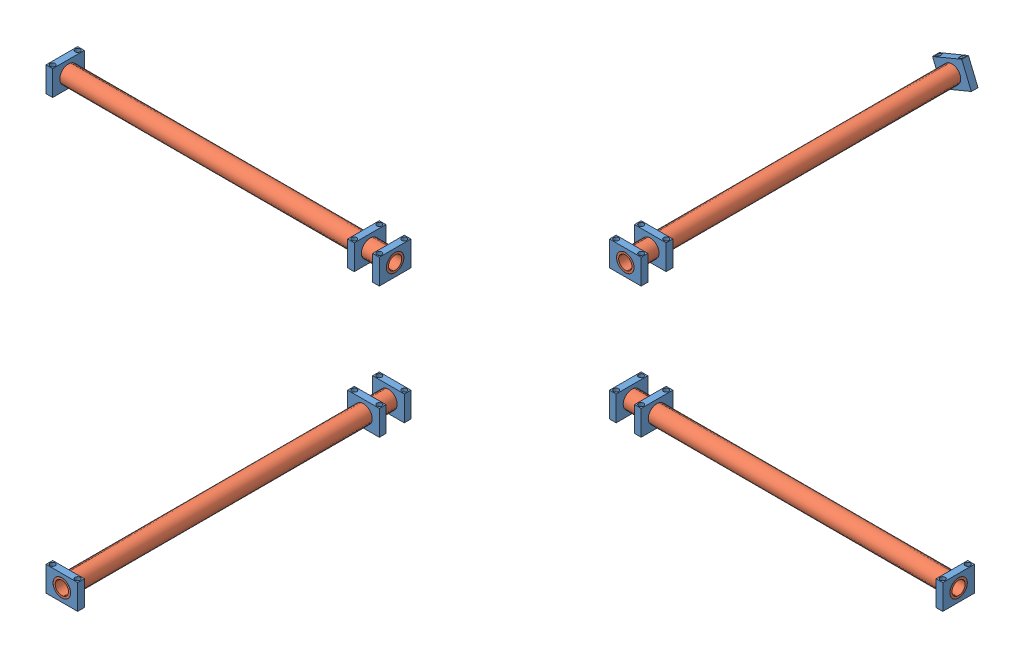
SolidWorks assembly new_drone_full_body, configuration Default. Lengths in mm.
Overall size (538.13 21.13 538.13).
18 component instances, 3 part files, 80 mates.
Components (placement in the parent):
- base-plate_drone_new-1: base-plate_drone_new [Default] at (-94378.7064 -1163.9739 82221.6136) (suppressed, hidden)
- holder-1: holder [Default] at (71.6083 102.2761 266.6718) x (1 0 0) z (0 1 0) size (19 4 15)
- holder-2: holder [Default] at (71.5935 87.2761 247.6718) x (1 0 0) z (0 -1 0) size (19 4 15)
- holder-4: holder [Default] at (12.0275 87.2761 169.1058) x (0 0 1) z (0 -1 0) size (19 4 15)
- holder-6: holder [Default] at (-6.9728 87.2761 188.1203) x (0.00014 0 -1) z (0 -1 0) size (19 4 15)
- holder-7: holder [Default] at (90.5787 102.2761 90.5398) x (-1 0 0) z (0 1 0) size (19 4 15)
- holder-8: holder [Default] at (71.5935 87.2761 105.5398) x (1 0 0) z (0 -1 0) size (19 4 15)
- holder-9: holder [Default] at (165.1595 102.2761 169.091) x (0 0 1) z (0 1 0) size (19 4 15)
- holder-10: holder [Default] at (150.1595 87.2761 188.1058) x (0 0 -1) z (0 -1 0) size (19 4 15)
- New_arm-1: New_arm [Default] at (350.1595 94.7761 178.6058) x (0 0 1) z (1 0 0) size (10.5 10.5 200)
- New_arm-2: New_arm [Default] at (81.0935 94.7761 109.5398) size (10.5 10.5 200)
- New_arm-3: New_arm [Default] at (12.0275 94.7761 178.6058) x (0 0.007654 -0.999971) z (1 0 0) size (10.5 10.5 200)
- New_arm-4: New_arm [Default] at (81.0935 94.7761 447.6718) size (10.5 10.5 200)
- base-plate_drone_new-2: base-plate_drone_new [Default] at (-94378.7064 -1146.4739 82221.6136) (suppressed, hidden)
- holder-11: holder [Default] at (69.4452 98.0651 -86.4602) x (0.923728 0.383049 0) z (-0.383049 0.923728 0) size (19 4 15)
- holder-12: holder [Default] at (-187.9725 102.2761 169.1058) x (0 0 1) z (0 1 0) size (19 4 15)
- holder-13: holder [Default] at (90.5935 102.2761 443.6718) x (-1 0 0) z (0 1 0) size (19 4 15)
- holder-14: holder [Default] at (346.1595 102.2761 169.1058) x (0 0 1) z (0 1 0) size (19 4 15)
Mates (geometry in assembly coordinates):
- Coincident6: coincident: circle of base-plate_drone_new-1; circle of holder-1
- Concentric1: concentric: circle of base-plate_drone_new-1; circle of holder-1
- Coincident8: coincident: circle of base-plate_drone_new-1; circle of holder-2
- Coincident9: coincident: circle of base-plate_drone_new-1; circle of holder-2
- Coincident16: coincident: circle of base-plate_drone_new-1; circle of holder-4
- Coincident17: coincident: circle of base-plate_drone_new-1; circle of holder-4
- Coincident20: coincident: circle of base-plate_drone_new-1; circle of holder-6
- Parallel2: parallel: cylinder of base-plate_drone_new-1 through (-4.9725 87.2761 171.1058) axis (0 -1 0) radius 1.5; cylinder of holder-6 through (-4.9704 102.2761 171.1206) axis (0 -1 0) radius 1.5
- Coincident22: coincident: circle of base-plate_drone_new-1; circle of holder-7
- Parallel3: parallel: cylinder of base-plate_drone_new-1 through (88.5935 87.2761 92.5398) axis (0 -1 0) radius 1.5; cylinder of holder-7 through (88.5787 87.2761 92.5398) axis (0 1 0) radius 1.5
- Coincident24: coincident: circle of base-plate_drone_new-1; circle of holder-8
- Coincident25: coincident: circle of base-plate_drone_new-1; circle of holder-8
- Coincident27: coincident: circle of base-plate_drone_new-1; circle of holder-9
- Parallel5: parallel: cylinder of base-plate_drone_new-1 through (167.1595 87.2761 186.1058) axis (0 -1 0) radius 1.5; cylinder of holder-9 through (167.1595 87.2761 186.091) axis (0 1 0) radius 1.5
- Coincident28: coincident: circle of base-plate_drone_new-1; circle of holder-10
- Coincident29: coincident: circle of base-plate_drone_new-1; circle of holder-10
- Concentric11: concentric: cylinder of holder-4 through (8.0275 94.7761 178.6058) axis (1 0 0) radius 5.25; cylinder of New_arm-3 through (-187.9725 94.7761 178.6058) axis (1 0 0) radius 5.25
- Coincident30: coincident: plane of holder-4 through (12.0275 87.2761 169.1058) normal (1 0 0); plane of New_arm-3 through (12.0275 94.7761 178.6058) normal (1 0 0)
- Concentric12: concentric: cylinder of holder-8 through (81.0935 94.7761 109.5398) axis (0 0 -1) radius 5.25; cylinder of New_arm-2 through (81.0935 94.7761 -90.4602) axis (0 0 1) radius 5.25
- Coincident31: coincident: plane of holder-8 through (71.5935 87.2761 109.5398) normal (0 0 1); plane of New_arm-2 through (81.0935 94.7761 109.5398) normal (0 0 1)
- Concentric13: concentric: cylinder of holder-2 through (81.0935 94.7761 251.6718) axis (0 0 -1) radius 5.25; cylinder of New_arm-4 through (81.0935 94.7761 247.6718) axis (0 0 1) radius 5.25
- Coincident32: coincident: plane of holder-2 through (71.5935 87.2761 247.6718) normal (0 0 -1); plane of New_arm-4 through (81.0935 94.7761 247.6718) normal (0 0 -1)
- Concentric14: concentric: cylinder of holder-10 through (154.1595 94.7761 178.6058) axis (-1 0 0) radius 5.25; cylinder of New_arm-1 through (150.1595 94.7761 178.6058) axis (1 0 0) radius 5.25
- Coincident33: coincident: plane of holder-10 through (150.1595 87.2761 188.1058) normal (-1 0 0); plane of New_arm-1 through (150.1595 94.7761 178.6058) normal (-1 0 0)
- Coincident34: coincident: circle of holder-7; circle of base-plate_drone_new-2
- Parallel6: parallel: cylinder of holder-7 through (88.5787 87.2761 92.5398) axis (0 1 0) radius 1.5; cylinder of base-plate_drone_new-2 through (88.5935 104.7761 92.5398) axis (0 -1 0) radius 1.5
- Coincident36: coincident: circle of holder-8; circle of base-plate_drone_new-2
- Parallel7: parallel: cylinder of holder-8 through (73.5935 102.2761 107.5398) axis (0 -1 0) radius 1.5; cylinder of base-plate_drone_new-2 through (73.5935 104.7761 107.5398) axis (0 -1 0) radius 1.5
- Coincident37: coincident: circle of holder-8; circle of base-plate_drone_new-2
- Parallel8: parallel: cylinder of holder-9 through (167.1595 87.2761 186.091) axis (0 1 0) radius 1.5; cylinder of base-plate_drone_new-2 through (167.1595 104.7761 186.1058) axis (0 -1 0) radius 1.5
- Parallel9: parallel: cylinder of holder-9 through (167.1595 87.2761 171.091) axis (0 1 0) radius 1.5; cylinder of base-plate_drone_new-2 through (167.1595 104.7761 171.091) axis (0 -1 0) radius 1.5
- Parallel10: parallel: cylinder of holder-10 through (152.1595 102.2761 171.1058) axis (0 -1 0) radius 1.5; cylinder of base-plate_drone_new-2 through (152.1595 104.7761 171.1058) axis (0 -1 0) radius 1.5
- Parallel11: parallel: cylinder of holder-10 through (152.1595 102.2761 186.1058) axis (0 -1 0) radius 1.5; cylinder of base-plate_drone_new-2 through (152.1595 104.7761 186.1058) axis (0 -1 0) radius 1.5
- Parallel12: parallel: cylinder of holder-1 through (88.6083 87.2761 264.6718) axis (0 1 0) radius 1.5; cylinder of base-plate_drone_new-2 through (88.6083 104.7761 264.6718) axis (0 -1 0) radius 1.5
- Parallel13: parallel: cylinder of holder-2 through (88.5935 102.2761 249.6718) axis (0 -1 0) radius 1.5; cylinder of base-plate_drone_new-2 through (88.5935 104.7761 249.6718) axis (0 -1 0) radius 1.5
- Parallel14: parallel: cylinder of holder-2 through (73.5935 102.2761 249.6718) axis (0 -1 0) radius 1.5; cylinder of base-plate_drone_new-2 through (73.5935 104.7761 249.6718) axis (0 -1 0) radius 1.5
- Parallel15: parallel: cylinder of holder-1 through (73.6083 87.2761 264.6718) axis (0 1 0) radius 1.5; cylinder of base-plate_drone_new-2 through (73.5935 104.7761 264.6718) axis (0 -1 0) radius 1.5
- Coincident40: coincident: circle of holder-4; circle of base-plate_drone_new-2
- Coincident42: coincident: circle of holder-6; circle of base-plate_drone_new-2
- Parallel19: parallel: cylinder of holder-6 through (-4.9704 102.2761 171.1206) axis (0 -1 0) radius 1.5; cylinder of base-plate_drone_new-2 through (-4.9725 104.7761 171.1058) axis (0 -1 0) radius 1.5
- Lock1: lock: unknown of holder-6; unknown of base-plate_drone_new-2
- Lock2: lock: unknown of holder-4; unknown of base-plate_drone_new-2
- Lock3: lock: unknown of holder-4; unknown of base-plate_drone_new-2
- Lock4: lock: unknown of holder-6; unknown of base-plate_drone_new-2
- Lock5: lock: unknown of holder-7; unknown of base-plate_drone_new-2
- Lock6: lock: unknown of holder-7; unknown of base-plate_drone_new-2
- Lock7: lock: unknown of holder-8; unknown of base-plate_drone_new-2
- Lock8: lock: unknown of holder-8; unknown of base-plate_drone_new-2
- Lock9: lock: unknown of base-plate_drone_new-1; unknown of holder-8
- Lock10: lock: unknown of holder-9; unknown of base-plate_drone_new-2
- Lock11: lock: unknown of base-plate_drone_new-1; unknown of holder-9
- Lock12: lock: unknown of holder-10; unknown of base-plate_drone_new-2
- Lock13: lock: unknown of base-plate_drone_new-1; unknown of holder-10
- Lock14: lock: unknown of holder-10; unknown of base-plate_drone_new-2
- Lock15: lock: unknown of base-plate_drone_new-1; unknown of holder-10
- Lock16: lock: unknown of holder-9; unknown of base-plate_drone_new-2
- Lock17: lock: unknown of base-plate_drone_new-1; unknown of holder-9
- Lock18: lock: unknown of holder-2; unknown of base-plate_drone_new-2
- Lock19: lock: unknown of base-plate_drone_new-1; unknown of holder-2
- Lock20: lock: unknown of holder-1; unknown of base-plate_drone_new-2
- Lock21: lock: unknown of base-plate_drone_new-1; unknown of holder-1
- Lock22: lock: unknown of holder-1; unknown of base-plate_drone_new-2
- Lock23: lock: unknown of base-plate_drone_new-1; unknown of holder-1
- Lock24: lock: unknown of holder-2; unknown of base-plate_drone_new-2
- Lock25: lock: unknown of base-plate_drone_new-1; unknown of holder-2
- Lock26: lock: unknown of holder-8; unknown of New_arm-2
- Lock27: lock: unknown of holder-4; unknown of New_arm-3
- Lock28: lock: unknown of holder-2; unknown of New_arm-4
- Lock29: lock: unknown of holder-10; unknown of New_arm-1
- Concentric20: concentric: cylinder of New_arm-2 through (81.0935 94.7761 -90.4602) axis (0 0 1) radius 5.25; cylinder of holder-11 through (81.0935 94.7761 -90.4602) axis (0 0 1) radius 5.25
- Lock30: lock: unknown of New_arm-2; unknown of holder-11
- Concentric21: concentric: cylinder of New_arm-3 through (-187.9725 94.7761 178.6058) axis (1 0 0) radius 5.25; cylinder of holder-12 through (-183.9725 94.7761 178.6058) axis (-1 0 0) radius 5.25
- Coincident51: coincident: plane of New_arm-3 through (-187.9725 94.7761 178.6058) normal (-1 0 0); plane of holder-12 through (-187.9725 102.2761 169.1058) normal (-1 0 0)
- Lock32: lock: unknown of New_arm-3; unknown of holder-12
- Concentric22: concentric: cylinder of New_arm-4 through (81.0935 94.7761 247.6718) axis (0 0 1) radius 5.25; cylinder of holder-13 through (81.0935 94.7761 447.6718) axis (0 0 -1) radius 5.25
- Coincident52: coincident: plane of New_arm-4 through (81.0935 94.7761 447.6718) normal (0 0 1); plane of holder-13 through (90.5935 102.2761 447.6718) normal (0 0 1)
- Lock33: lock: unknown of New_arm-4; unknown of holder-13
- Concentric23: concentric: cylinder of New_arm-1 through (150.1595 94.7761 178.6058) axis (1 0 0) radius 5.25; cylinder of holder-14 through (350.1595 94.7761 178.6058) axis (-1 0 0) radius 5.25
- Coincident54: coincident: plane of New_arm-1 through (350.1595 94.7761 178.6058) normal (1 0 0); plane of holder-14 through (350.1595 102.2761 169.1058) normal (1 0 0)
- Lock34: lock: unknown of New_arm-1; unknown of holder-14
